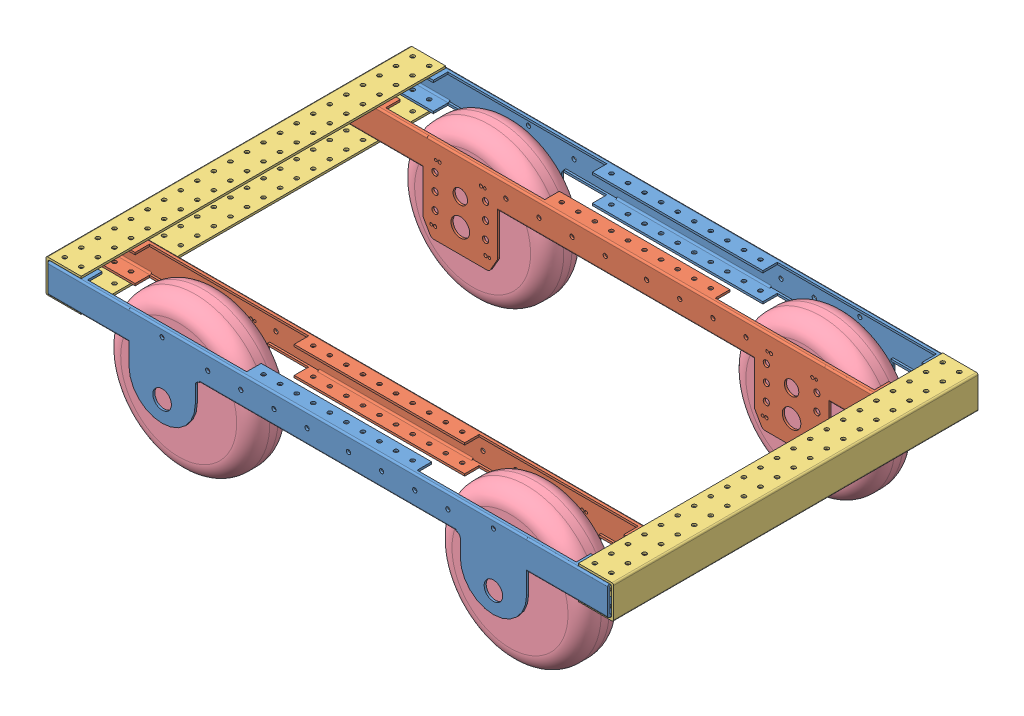
SolidWorks assembly protoAssemSan, configuration Default. Lengths in mm.
Overall size (870.31 228.6 564.98).
10 component instances, 4 part files, 22 mates.
Components (placement in the parent):
- protoLiftedChassis-1: protoLiftedChassis [Default] at (51.4507 551.7625 745.5394) size (858.52 127 28.57)
- protoLiftedChassis-2: protoLiftedChassis [Default] at (737.2507 551.7625 1310.5155) x (-1 0 0) z (0 0 -1) size (858.52 127 28.57)
- protoLiftedChassisInnerOmega-1: protoLiftedChassisInnerOmega [Default] at (737.2507 551.7625 853.3155) x (-1 0 0) z (0 0 -1) size (858.52 131.57 28.57)
- protoLiftedChassisInnerOmega-2: protoLiftedChassisInnerOmega [Default] at (51.4507 551.7625 1202.7394) size (858.52 131.57 28.57)
- protoLiftedChassisShort-1: protoLiftedChassisShort [Default] at (-34.4521 580.3375 1307.4275) x (0 0 -1) z (1 0 0) size (558.8 50.8 53.98)
- protoLiftedChassisShort-2: protoLiftedChassisShort [Default] at (823.1535 580.3375 748.6275) x (0 0 1) z (-1 0 0) size (558.8 50.8 53.98)
- 9inchWheelPlaceholder-1: 9inchWheelPlaceholder [Default] at (140.3507 532.7125 802.6894) x (1 0 0) z (0 1 0) size (228.6 63.5 228.6)
- 9inchWheelPlaceholder-2: 9inchWheelPlaceholder [Default] at (648.3507 532.7125 1253.3655) x (1 0 0) z (0 -1 0) size (228.6 63.5 228.6)
- 9inchWheelPlaceholder-3: 9inchWheelPlaceholder [Default] at (140.3507 532.7125 1253.3655) x (1 0 0) z (0 -1 0) size (228.6 63.5 228.6)
- 9inchWheelPlaceholder-4: 9inchWheelPlaceholder [Default] at (648.3507 532.7125 802.6894) x (1 0 0) z (0 1 0) size (228.6 63.5 228.6)
Mates (geometry in assembly coordinates):
- Concentric1: concentric anti-aligned: cylinder of protoLiftedChassis-2 through (-24.7493 551.7625 1294.7275) axis (0 1 0) radius 3.175; cylinder of protoLiftedChassisShort-1 through (-24.7493 637.4875 1294.7275) axis (0 -1 0) radius 3.175
- Concentric2: concentric anti-aligned: cylinder of protoLiftedChassis-2 through (813.4507 551.7625 1294.7275) axis (0 1 0) radius 3.175; cylinder of protoLiftedChassisShort-2 through (813.4507 637.4875 1294.7275) axis (0 -1 0) radius 3.175
- Coincident1: coincident anti-aligned: plane of protoLiftedChassis-2 through (788.0507 627.9625 1307.3405) normal (0 1 0); plane of protoLiftedChassisShort-1 through (13.1729 627.9625 748.6275) normal (0 -1 0)
- Coincident2: coincident anti-aligned: plane of protoLiftedChassis-2 through (788.0507 627.9625 1307.3405) normal (0 1 0); plane of protoLiftedChassisShort-2 through (775.5285 627.9625 1307.4275) normal (0 -1 0)
- Concentric3: concentric anti-aligned: cylinder of protoLiftedChassis-1 through (-24.7493 551.7625 761.3275) axis (0 1 0) radius 3.175; cylinder of protoLiftedChassisShort-1 through (-24.7493 637.4875 761.3275) axis (0 -1 0) radius 3.175
- Concentric4: concentric anti-aligned: cylinder of protoLiftedChassis-1 through (813.4507 551.7625 761.3275) axis (0 1 0) radius 3.175; cylinder of protoLiftedChassisShort-2 through (813.4507 637.4875 761.3275) axis (0 -1 0) radius 3.175
- Coincident3: coincident anti-aligned: plane of protoLiftedChassis-1 through (0.6507 627.9625 748.7144) normal (0 1 0); plane of protoLiftedChassisShort-1 through (13.1729 627.9625 748.6275) normal (0 -1 0)
- Concentric5: concentric anti-aligned: cylinder of protoLiftedChassis-2 through (788.0507 551.7625 1294.7275) axis (0 1 0) radius 3.175; cylinder of protoLiftedChassisShort-2 through (788.0507 637.4875 1294.7275) axis (0 -1 0) radius 3.175
- Concentric6: concentric anti-aligned: cylinder of protoLiftedChassisInnerOmega-1 through (813.4507 551.7625 837.5275) axis (0 1 0) radius 3.175; cylinder of protoLiftedChassisShort-2 through (813.4507 637.4875 837.5275) axis (0 -1 0) radius 3.175
- Concentric7: concentric anti-aligned: cylinder of protoLiftedChassisInnerOmega-1 through (-24.7493 551.7625 837.5275) axis (0 1 0) radius 3.175; cylinder of protoLiftedChassisShort-1 through (-24.7493 637.4875 837.5275) axis (0 -1 0) radius 3.175
- Coincident4: coincident anti-aligned: plane of protoLiftedChassisInnerOmega-1 through (788.0507 627.9625 850.1405) normal (0 1 0); plane of protoLiftedChassisShort-1 through (13.1729 627.9625 748.6275) normal (0 -1 0)
- Concentric8: concentric anti-aligned: cylinder of protoLiftedChassisInnerOmega-2 through (813.4507 551.7625 1218.5275) axis (0 1 0) radius 3.175; cylinder of protoLiftedChassisShort-2 through (813.4507 637.4875 1218.5275) axis (0 -1 0) radius 3.175
- Concentric9: concentric anti-aligned: cylinder of protoLiftedChassisInnerOmega-2 through (-24.7493 551.7625 1218.5275) axis (0 1 0) radius 3.175; cylinder of protoLiftedChassisShort-1 through (-24.7493 637.4875 1218.5275) axis (0 -1 0) radius 3.175
- Coincident5: coincident anti-aligned: plane of protoLiftedChassisInnerOmega-2 through (0.6507 627.9625 1205.9144) normal (0 1 0); plane of protoLiftedChassisShort-1 through (13.1729 627.9625 748.6275) normal (0 -1 0)
- Distance1: distance = 22.225 mm anti-aligned: plane of 9inchWheelPlaceholder-3 through (140.3507 532.7125 1285.1155) normal (0 0 1); plane of protoLiftedChassis-2 through (737.2507 551.7625 1307.3405) normal (0 0 -1)
- Distance2: distance = 22.225 mm anti-aligned: plane of 9inchWheelPlaceholder-2 through (648.3507 532.7125 1285.1155) normal (0 0 1); plane of protoLiftedChassis-2 through (737.2507 551.7625 1307.3405) normal (0 0 -1)
- Distance3: distance = 22.225 mm anti-aligned: plane of 9inchWheelPlaceholder-4 through (648.3507 532.7125 770.9394) normal (0 0 -1); plane of protoLiftedChassis-1 through (51.4507 551.7625 748.7144) normal (0 0 1)
- Distance4: distance = 22.225 mm anti-aligned: plane of protoLiftedChassis-1 through (51.4507 551.7625 748.7144) normal (0 0 1); plane of 9inchWheelPlaceholder-1 through (140.3507 532.7125 770.9394) normal (0 0 -1)
- Concentric10: concentric anti-aligned: cylinder of protoLiftedChassisInnerOmega-2 through (140.3507 532.7125 1205.9144) axis (0 0 -1) radius 14.2875; cylinder of 9inchWheelPlaceholder-3 through (140.3507 532.7125 1177.9275) axis (0 0 1) radius 6.35
- Concentric11: concentric anti-aligned: cylinder of protoLiftedChassisInnerOmega-2 through (648.3507 532.7125 1205.9144) axis (0 0 -1) radius 14.2875; cylinder of 9inchWheelPlaceholder-2 through (648.3507 532.7125 1177.9275) axis (0 0 1) radius 6.35
- Concentric12: concentric anti-aligned: cylinder of protoLiftedChassisInnerOmega-1 through (648.3507 532.7125 850.1405) axis (0 0 1) radius 14.2875; cylinder of 9inchWheelPlaceholder-4 through (648.3507 532.7125 878.1274) axis (0 0 -1) radius 6.35
- Concentric13: concentric anti-aligned: cylinder of protoLiftedChassisInnerOmega-1 through (140.3507 532.7125 850.1405) axis (0 0 1) radius 14.2875; cylinder of 9inchWheelPlaceholder-1 through (140.3507 532.7125 878.1274) axis (0 0 -1) radius 6.35
